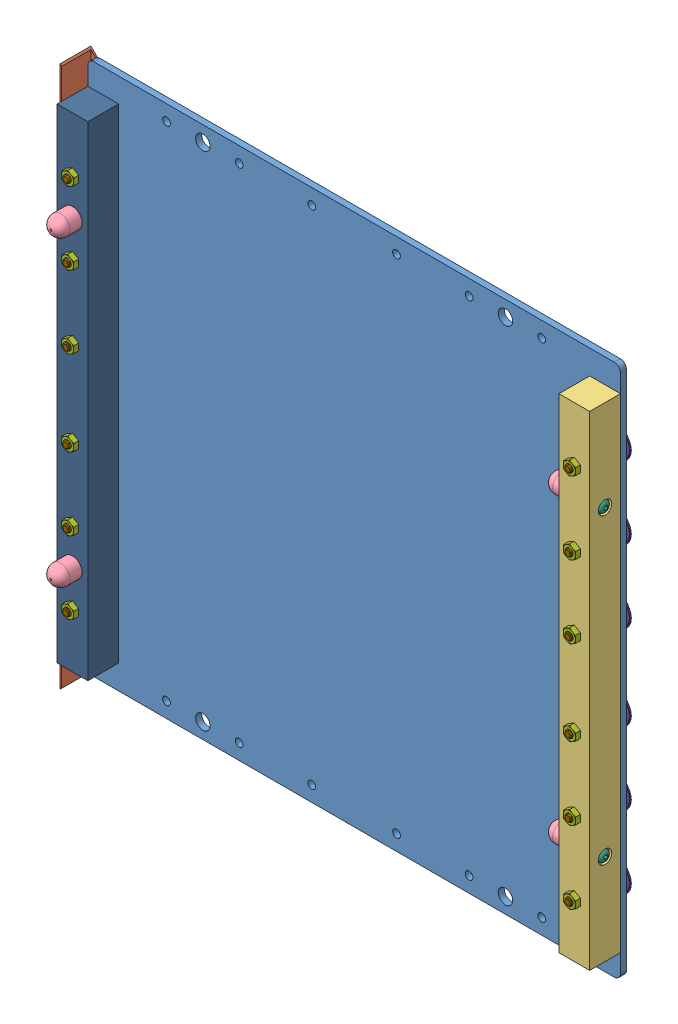
SolidWorks assembly Bed_MainAssembly, configuration Default. Lengths in mm.
Overall size (447.67 447.54 58.62).
61 component instances, 12 part files, 129 mates.
Components (placement in the parent):
- Bed_5mm-1: Bed_5mm [Default] at origin size (440 440 5)
- BedFrame-1: BedFrame [Default] at (-223.77 0 -1.27) x (0 0 1) z (0 1 0) size (25.4 25.4 447.54) (hidden)
- BedFrame-2: BedFrame [Default] at (0 -223.77 -1.27) x (0 0 1) z (-1 0 0) size (25.4 25.4 447.54) (hidden)
- BedFrame-3: BedFrame [Default] at (223.77 0 -1.27) x (0 0 1) z (0 -1 0) size (25.4 25.4 447.54) (hidden)
- BedFrame-4: BedFrame [Default] at (0 223.77 -1.27) x (0 0 1) z (1 0 0) size (25.4 25.4 447.54) (hidden)
- BedFrame_DelrinBar-1: BedFrame_DelrinBar [Default] at (207.3 0 17.7) x (0 0 -1) z (0 -1 0) size (25.4 25.4 400)
- CJPQTBB12_16-1: CJPQTBB12_16 [Default] at (194.6 125 17.7) x (-1 0 0) z (0 -0.914699 0.404136) size (32.96 16 16)
- CJPQTBB12_16-2: CJPQTBB12_16 [Default] at (194.6 -125 17.7) x (-1 0 0) z (0 -0.761161 -0.648564) size (32.96 16 16)
- M5_ss_93475A240-1: M5_ss_93475A240 [93475A240] at (217 -125 17.7) x (0 0 1) z (-1 0 0) size (10 10 0.9)
- M5_ss_93475A240-2: M5_ss_93475A240 [93475A240] at (217 125 17.7) x (0 0 1) z (-1 0 0) size (10 10 0.9)
- button_M5x20_92095A214-1: button_M5x20_92095A214 [92095A214] at (197.9 125 17.7) x (0 0 1) z (-1 0 0) size (9.5 9.5 23.15)
- button_M5x20_92095A214-2: button_M5x20_92095A214 [92095A214] at (197.9 -125 17.7) x (0 0.963052 -0.269316) z (-1 0 0) size (9.5 9.5 23.15)
- Captive_M6_97648A440-1: Captive_M6_97648A440 [97648A440] at (207.3 155 34.5) size (10 11.55 5.74)
- Captive_M6_97648A440-2: Captive_M6_97648A440 [97648A440] at (207.3 95 34.5) size (10 11.55 5.74)
- Captive_M6_97648A440-3: Captive_M6_97648A440 [97648A440] at (207.3 35 34.5) size (10 11.55 5.74)
- Captive_M6_97648A440-4: Captive_M6_97648A440 [97648A440] at (207.3 -35 34.5) size (10 11.55 5.74)
- Captive_M6_97648A440-5: Captive_M6_97648A440 [97648A440] at (207.3 -95 34.5) size (10 11.55 5.74)
- Captive_M6_97648A440-6: Captive_M6_97648A440 [97648A440] at (207.3 -155 34.5) size (10 11.55 5.74)
- 1-4_silicone_ss_91195A107-1: 1-4_silicone_ss_91195A107 [91195A107] at (207.3 -155 -3.9688) x (-0.923728 -0.383049 0) z (0 0 -1) size (25.4 25.4 3.97)
- 1-4_silicone_ss_91195A107-2: 1-4_silicone_ss_91195A107 [91195A107] at (207.3 -95 -3.9688) x (-0.923728 -0.383049 0) z (0 0 -1) size (25.4 25.4 3.97)
- 1-4_silicone_ss_91195A107-3: 1-4_silicone_ss_91195A107 [91195A107] at (207.3 -35 -3.9688) x (-0.923728 -0.383049 0) z (0 0 -1) size (25.4 25.4 3.97)
- 1-4_silicone_ss_91195A107-4: 1-4_silicone_ss_91195A107 [91195A107] at (207.3 35 -3.9688) x (-0.923728 -0.383049 0) z (0 0 -1) size (25.4 25.4 3.97)
- 1-4_silicone_ss_91195A107-5: 1-4_silicone_ss_91195A107 [91195A107] at (207.3 95 -3.9688) x (-0.923728 -0.383049 0) z (0 0 -1) size (25.4 25.4 3.97)
- 1-4_silicone_ss_91195A107-6: 1-4_silicone_ss_91195A107 [91195A107] at (207.3 155 -3.9688) x (-0.923728 -0.383049 0) z (0 0 -1) size (25.4 25.4 3.97)
- M6x40_91292A142-2: M6x40_91292A142 [91292A142] at (207.3 155 36.0312) size (10 10 46.57)
- M6x40_91292A142-3: M6x40_91292A142 [91292A142] at (207.3 95 36.0312) size (10 10 46.57)
- M6x40_91292A142-4: M6x40_91292A142 [91292A142] at (207.3 35 36.0312) size (10 10 46.57)
- M6x40_91292A142-5: M6x40_91292A142 [91292A142] at (207.3 -35 36.0312) size (10 10 46.57)
- M6x40_91292A142-6: M6x40_91292A142 [91292A142] at (207.3 -95 36.0312) size (10 10 46.57)
- M6x40_91292A142-7: M6x40_91292A142 [91292A142] at (207.3 -155 36.0312) size (10 10 46.57)
- BedFrame_LowerBar-1: BedFrame_LowerBar [Default] at (-207.3 0 17.7) x (0 0 -1) z (0 -1 0) size (25.4 25.4 400)
- CJPQTBB12_16-5: CJPQTBB12_16 [Default] at (-207.3 125 30.4) x (0 0 1) z (-1 0 0) size (32.96 16 16)
- CJPQTBB12_16-6: CJPQTBB12_16 [Default] at (-207.3 -125 30.4) x (0 0 1) z (-1 0 0) size (32.96 16 16)
- M5_ss_93475A240-3: M5_ss_93475A240 [93475A240] at (-207.3 125 8) size (10 10 0.9)
- M5_ss_93475A240-4: M5_ss_93475A240 [93475A240] at (-207.3 -125 8) size (10 10 0.9)
- button_M5x20_92095A214-3: button_M5x20_92095A214 [92095A214] at (-207.3 125 27.1) size (9.5 9.5 23.15)
- button_M5x20_92095A214-4: button_M5x20_92095A214 [92095A214] at (-207.3 -125 27.1) size (9.5 9.5 23.15)
- Captive_M6_97648A440-7: Captive_M6_97648A440 [97648A440] at (-207.3 -155 34.5) size (10 11.55 5.74)
- Captive_M6_97648A440-8: Captive_M6_97648A440 [97648A440] at (-207.3 -35 34.5) size (10 11.55 5.74)
- Captive_M6_97648A440-9: Captive_M6_97648A440 [97648A440] at (-207.3 35 34.5) size (10 11.55 5.74)
- Captive_M6_97648A440-10: Captive_M6_97648A440 [97648A440] at (-207.3 95 34.5) size (10 11.55 5.74)
- Captive_M6_97648A440-11: Captive_M6_97648A440 [97648A440] at (-207.3 -95 34.5) size (10 11.55 5.74)
- Captive_M6_97648A440-12: Captive_M6_97648A440 [97648A440] at (-207.3 155 34.5) size (10 11.55 5.74)
- 1-4_silicone_99604A115-1: 1-4_silicone_99604A115 [99604A115] at (-207.3 -155 0) size (15.88 15.88 2.36)
- 1-4_silicone_99604A115-2: 1-4_silicone_99604A115 [99604A115] at (-207.3 -95 0) size (15.88 15.88 2.36)
- 1-4_silicone_99604A115-3: 1-4_silicone_99604A115 [99604A115] at (-207.3 -35 0) size (15.88 15.88 2.36)
- 1-4_silicone_99604A115-4: 1-4_silicone_99604A115 [99604A115] at (-207.3 35 0) size (15.88 15.88 2.36)
- 1-4_silicone_99604A115-5: 1-4_silicone_99604A115 [99604A115] at (-207.3 95 0) size (15.88 15.88 2.36)
- 1-4_silicone_99604A115-6: 1-4_silicone_99604A115 [99604A115] at (-207.3 155 0) size (15.88 15.88 2.36)
- M6_ss_93475A250-1: M6_ss_93475A250 [93475A250] at (-207.3 -155 -2.3622) size (12 12 1.4)
- M6_ss_93475A250-2: M6_ss_93475A250 [93475A250] at (-207.3 -95 -2.3622) size (12 12 1.4)
- M6_ss_93475A250-3: M6_ss_93475A250 [93475A250] at (-207.3 -35 -2.3622) size (12 12 1.4)
- M6_ss_93475A250-4: M6_ss_93475A250 [93475A250] at (-207.3 35 -2.3622) size (12 12 1.4)
- M6_ss_93475A250-5: M6_ss_93475A250 [93475A250] at (-207.3 95 -2.3622) size (12 12 1.4)
- M6_ss_93475A250-6: M6_ss_93475A250 [93475A250] at (-207.3 155 -2.3622) size (12 12 1.4)
- M6x40_91292A142-8: M6x40_91292A142 [91292A142] at (-207.3 -155 36.2378) size (10 10 46.57)
- M6x40_91292A142-9: M6x40_91292A142 [91292A142] at (-207.3 -95 36.2378) size (10 10 46.57)
- M6x40_91292A142-10: M6x40_91292A142 [91292A142] at (-207.3 -35 36.2378) size (10 10 46.57)
- M6x40_91292A142-11: M6x40_91292A142 [91292A142] at (-207.3 35 36.2378) size (10 10 46.57)
- M6x40_91292A142-12: M6x40_91292A142 [91292A142] at (-207.3 95 36.2378) size (10 10 46.57)
- M6x40_91292A142-13: M6x40_91292A142 [91292A142] at (-207.3 155 36.2378) size (10 10 46.57)
Mates (geometry in assembly coordinates):
- Coincident1: coincident aligned: plane of Bed_5mm-1 through (0 0 0) normal (0 0 1); plane of assembly through (0 0 0) normal (0 0 1)
- Coincident2: coincident aligned: plane of Bed_5mm-1 through (0 0 0) normal (0 1 0); plane of assembly through (0 0 0) normal (0 1 0)
- Coincident3: coincident aligned: plane of Bed_5mm-1 through (0 0 0) normal (1 0 0); plane of assembly through (0 0 0) normal (1 0 0)
- Coincident4: coincident anti-aligned: plane of Bed_5mm-1 through (-220 -220 0) normal (0 0 -1); plane of BedFrame-1 through (-222.5 -304.8 0) normal (0 0 1)
- Coincident5: coincident anti-aligned: plane of Bed_5mm-1 through (-220 -220 0) normal (0 0 -1); plane of BedFrame-2 through (304.8 -222.5 0) normal (0 0 1)
- Coincident6: coincident anti-aligned: plane of Bed_5mm-1 through (-220 -220 0) normal (0 0 -1); plane of BedFrame-3 through (222.5 304.8 0) normal (0 0 1)
- Coincident7: coincident anti-aligned: plane of Bed_5mm-1 through (-220 -220 0) normal (0 0 -1); plane of BedFrame-4 through (-304.8 222.5 0) normal (0 0 1)
- Coincident8: coincident anti-aligned: plane of BedFrame-1 through (-198.37 -198.37 24.13) normal (0.707107 -0.707107 0); plane of BedFrame-2 through (-223.77 -223.77 24.13) normal (-0.707107 0.707107 0)
- Coincident10: coincident aligned: line of BedFrame-1 through (-223.77 -223.77 24.13) axis (0 0 -1); line of BedFrame-2 through (-223.77 -223.77 24.13) axis (0 0 -1)
- Coincident11: coincident anti-aligned: plane of BedFrame-2 through (198.37 -198.37 24.13) normal (0.707107 0.707107 0); plane of BedFrame-3 through (223.77 -223.77 24.13) normal (-0.707107 -0.707107 0)
- Coincident12: coincident aligned: line of BedFrame-2 through (223.77 -223.77 24.13) axis (0 0 -1); line of BedFrame-3 through (223.77 -223.77 24.13) axis (0 0 -1)
- Coincident13: coincident anti-aligned: plane of BedFrame-3 through (198.37 198.37 24.13) normal (-0.707107 0.707107 0); plane of BedFrame-4 through (223.77 223.77 24.13) normal (0.707107 -0.707107 0)
- Coincident14: coincident aligned: line of BedFrame-3 through (223.77 223.77 24.13) axis (0 0 -1); line of BedFrame-4 through (223.77 223.77 24.13) axis (0 0 -1)
- Coincident15: coincident aligned: plane of BedFrame-1 through (-223.77 0 -1.27) normal (0 1 0); plane of assembly through (0 0 0) normal (0 1 0)
- Coincident16: coincident anti-aligned: plane of Bed_5mm-1 through (0 0 0) normal (1 0 0); plane of BedFrame-2 through (0 -223.77 -1.27) normal (-1 0 0)
- Coincident17: coincident anti-aligned: plane of BedFrame_DelrinBar-1 through (207.3 0 17.7) normal (0 -1 0); plane of assembly through (0 0 0) normal (0 1 0)
- Coincident18: coincident anti-aligned: plane of Bed_5mm-1 through (-220 -220 5) normal (0 0 1); plane of BedFrame_DelrinBar-1 through (194.6 200 5) normal (0 0 -1)
- Coincident19: coincident aligned: plane of Bed_5mm-1 through (220 220 5) normal (1 0 0); plane of BedFrame_DelrinBar-1 through (220 200 5) normal (1 0 0)
- Concentric2: concentric aligned: cylinder of BedFrame_DelrinBar-1 through (230.8107 -125 17.7) axis (1 0 0) radius 6; cylinder of CJPQTBB12_16-2 through (194.5 -125 17.7) axis (1 0 0) radius 6
- Concentric3: concentric aligned: cylinder of BedFrame_DelrinBar-1 through (230.8107 125 17.7) axis (1 0 0) radius 6; cylinder of CJPQTBB12_16-1 through (194.5 125 17.7) axis (1 0 0) radius 6
- Coincident20: coincident anti-aligned: plane of BedFrame_DelrinBar-1 through (217 127.75 17.7) normal (1 0 0); plane of M5_ss_93475A240-2 through (217 125 17.7) normal (-1 0 0)
- Coincident21: coincident anti-aligned: plane of BedFrame_DelrinBar-1 through (217 -127.75 17.7) normal (1 0 0); plane of M5_ss_93475A240-1 through (217 -125 17.7) normal (-1 0 0)
- Concentric4: concentric anti-aligned: cylinder of BedFrame_DelrinBar-1 through (230.8107 -125 17.7) axis (1 0 0) radius 5.5563; cylinder of M5_ss_93475A240-1 through (217.9 -125 17.7) axis (-1 0 0) radius 5
- Concentric5: concentric anti-aligned: cylinder of BedFrame_DelrinBar-1 through (230.8107 125 17.7) axis (1 0 0) radius 5.5563; cylinder of M5_ss_93475A240-2 through (217.9 125 17.7) axis (-1 0 0) radius 5
- Concentric6: concentric anti-aligned: cylinder of BedFrame_DelrinBar-1 through (230.8107 125 17.7) axis (1 0 0) radius 5.5563; cylinder of button_M5x20_92095A214-1 through (220.65 125 17.7) axis (-1 0 0) radius 4.75
- Coincident22: coincident anti-aligned: plane of M5_ss_93475A240-2 through (217.9 125 17.7) normal (1 0 0); plane of button_M5x20_92095A214-1 through (217.9 125 17.7) normal (-1 0 0)
- Concentric7: concentric anti-aligned: cylinder of BedFrame_DelrinBar-1 through (230.8107 -125 17.7) axis (1 0 0) radius 5.5563; cylinder of button_M5x20_92095A214-2 through (220.65 -125 17.7) axis (-1 0 0) radius 4.75
- Coincident23: coincident anti-aligned: plane of M5_ss_93475A240-1 through (217.9 -125 17.7) normal (1 0 0); plane of button_M5x20_92095A214-2 through (217.9 -125 17.7) normal (-1 0 0)
- Coincident24: coincident anti-aligned: plane of BedFrame_DelrinBar-1 through (194.6 200 5) normal (-1 0 0); plane of CJPQTBB12_16-2 through (194.6 -125 17.7) normal (1 0 0)
- Coincident25: coincident anti-aligned: plane of BedFrame_DelrinBar-1 through (194.6 200 5) normal (-1 0 0); plane of CJPQTBB12_16-1 through (194.6 125 17.7) normal (1 0 0)
- Coincident26: coincident aligned: plane of Captive_M6_97648A440-1 through (202.3 163.6603 30.4) normal (0 0 -1); plane of Captive_M6_97648A440-6 through (202.3 -146.3397 30.4) normal (0 0 -1)
- Coincident27: coincident aligned: plane of Captive_M6_97648A440-4 through (202.3 -26.3397 30.4) normal (0 0 -1); plane of Captive_M6_97648A440-6 through (202.3 -146.3397 30.4) normal (0 0 -1)
- Coincident28: coincident aligned: plane of Captive_M6_97648A440-5 through (202.3 -86.3397 30.4) normal (0 0 -1); plane of Captive_M6_97648A440-6 through (202.3 -146.3397 30.4) normal (0 0 -1)
- Coincident29: coincident aligned: plane of Captive_M6_97648A440-3 through (202.3 43.6603 30.4) normal (0 0 -1); plane of Captive_M6_97648A440-6 through (202.3 -146.3397 30.4) normal (0 0 -1)
- Coincident30: coincident aligned: plane of Captive_M6_97648A440-2 through (202.3 103.6603 30.4) normal (0 0 -1); plane of Captive_M6_97648A440-6 through (202.3 -146.3397 30.4) normal (0 0 -1)
- Coincident31: coincident anti-aligned: plane of BedFrame_DelrinBar-1 through (194.6 200 30.4) normal (0 0 1); plane of Captive_M6_97648A440-6 through (202.3 -146.3397 30.4) normal (0 0 -1)
- Concentric8: concentric anti-aligned: cylinder of BedFrame_DelrinBar-1 through (207.3 -155 27.4) axis (0 0 1) radius 4; circle of Captive_M6_97648A440-6
- Concentric9: concentric anti-aligned: cylinder of BedFrame_DelrinBar-1 through (207.3 -95 27.4) axis (0 0 1) radius 4; circle of Captive_M6_97648A440-5
- Concentric10: concentric anti-aligned: cylinder of BedFrame_DelrinBar-1 through (207.3 -35 27.4) axis (0 0 1) radius 4; circle of Captive_M6_97648A440-4
- Concentric11: concentric anti-aligned: cylinder of BedFrame_DelrinBar-1 through (207.3 35 27.4) axis (0 0 1) radius 4; circle of Captive_M6_97648A440-3
- Concentric12: concentric anti-aligned: cylinder of BedFrame_DelrinBar-1 through (207.3 95 27.4) axis (0 0 1) radius 4; circle of Captive_M6_97648A440-2
- Concentric13: concentric anti-aligned: cylinder of BedFrame_DelrinBar-1 through (207.3 155 27.4) axis (0 0 1) radius 4; circle of Captive_M6_97648A440-1
- Coincident32: coincident aligned: plane of 1-4_silicone_ss_91195A107-1 through (207.3 -155 0) normal (0 0 1); plane of 1-4_silicone_ss_91195A107-2 through (207.3 -95 0) normal (0 0 1)
- Coincident33: coincident aligned: plane of 1-4_silicone_ss_91195A107-1 through (207.3 -155 0) normal (0 0 1); plane of 1-4_silicone_ss_91195A107-3 through (207.3 -35 0) normal (0 0 1)
- Coincident34: coincident aligned: plane of 1-4_silicone_ss_91195A107-1 through (207.3 -155 0) normal (0 0 1); plane of 1-4_silicone_ss_91195A107-4 through (207.3 35 0) normal (0 0 1)
- Coincident35: coincident aligned: plane of 1-4_silicone_ss_91195A107-1 through (207.3 -155 0) normal (0 0 1); plane of 1-4_silicone_ss_91195A107-5 through (207.3 95 0) normal (0 0 1)
- Coincident36: coincident aligned: plane of 1-4_silicone_ss_91195A107-1 through (207.3 -155 0) normal (0 0 1); plane of 1-4_silicone_ss_91195A107-6 through (207.3 155 0) normal (0 0 1)
- Coincident37: coincident anti-aligned: plane of Bed_5mm-1 through (-220 -220 0) normal (0 0 -1); plane of 1-4_silicone_ss_91195A107-1 through (207.3 -155 0) normal (0 0 1)
- Concentric15: concentric aligned: cylinder of BedFrame_DelrinBar-1 through (207.3 -155 30.4) axis (0 0 -1) radius 3.2; cylinder of 1-4_silicone_ss_91195A107-1 through (207.3 -155 38.0937) axis (0 0 -1) radius 12.065
- Concentric16: concentric aligned: cylinder of BedFrame_DelrinBar-1 through (207.3 -95 30.4) axis (0 0 -1) radius 3.2; cylinder of 1-4_silicone_ss_91195A107-2 through (207.3 -95 38.0937) axis (0 0 -1) radius 12.065
- Concentric17: concentric aligned: cylinder of BedFrame_DelrinBar-1 through (207.3 -35 30.4) axis (0 0 -1) radius 3.2; cylinder of 1-4_silicone_ss_91195A107-3 through (207.3 -35 38.0937) axis (0 0 -1) radius 12.065
- Concentric18: concentric aligned: cylinder of BedFrame_DelrinBar-1 through (207.3 35 30.4) axis (0 0 -1) radius 3.2; cylinder of 1-4_silicone_ss_91195A107-4 through (207.3 35 38.0937) axis (0 0 -1) radius 12.065
- Concentric19: concentric aligned: cylinder of BedFrame_DelrinBar-1 through (207.3 95 30.4) axis (0 0 -1) radius 3.2; cylinder of 1-4_silicone_ss_91195A107-5 through (207.3 95 38.0937) axis (0 0 -1) radius 12.065
- Concentric20: concentric aligned: cylinder of BedFrame_DelrinBar-1 through (207.3 155 30.4) axis (0 0 -1) radius 3.2; cylinder of 1-4_silicone_ss_91195A107-6 through (207.3 155 38.0937) axis (0 0 -1) radius 12.065
- Coincident38: coincident aligned: plane of M6x40_91292A142-6 through (207.3 -95 -3.9688) normal (0 0 1); plane of M6x40_91292A142-7 through (207.3 -155 -3.9688) normal (0 0 1)
- Coincident39: coincident aligned: plane of M6x40_91292A142-5 through (207.3 -35 -3.9688) normal (0 0 1); plane of M6x40_91292A142-7 through (207.3 -155 -3.9688) normal (0 0 1)
- Coincident40: coincident aligned: plane of M6x40_91292A142-4 through (207.3 35 -3.9688) normal (0 0 1); plane of M6x40_91292A142-7 through (207.3 -155 -3.9688) normal (0 0 1)
- Coincident41: coincident aligned: plane of M6x40_91292A142-3 through (207.3 95 -3.9688) normal (0 0 1); plane of M6x40_91292A142-7 through (207.3 -155 -3.9688) normal (0 0 1)
- Coincident42: coincident aligned: plane of M6x40_91292A142-2 through (207.3 155 -3.9688) normal (0 0 1); plane of M6x40_91292A142-7 through (207.3 -155 -3.9688) normal (0 0 1)
- Coincident43: coincident anti-aligned: plane of 1-4_silicone_ss_91195A107-2 through (207.3 -95 -3.9688) normal (0 0 -1); plane of M6x40_91292A142-7 through (207.3 -155 -3.9688) normal (0 0 1)
- Concentric21: concentric anti-aligned: cylinder of 1-4_silicone_ss_91195A107-1 through (207.3 -155 38.0937) axis (0 0 -1) radius 12.065; cylinder of M6x40_91292A142-7 through (207.3 -155 -9.9688) axis (0 0 1) radius 5
- Concentric22: concentric anti-aligned: cylinder of 1-4_silicone_ss_91195A107-2 through (207.3 -95 38.0937) axis (0 0 -1) radius 12.065; cylinder of M6x40_91292A142-6 through (207.3 -95 -9.9688) axis (0 0 1) radius 5
- Concentric23: concentric anti-aligned: cylinder of 1-4_silicone_ss_91195A107-3 through (207.3 -35 38.0937) axis (0 0 -1) radius 12.065; cylinder of M6x40_91292A142-5 through (207.3 -35 -9.9688) axis (0 0 1) radius 5
- Concentric24: concentric anti-aligned: cylinder of 1-4_silicone_ss_91195A107-4 through (207.3 35 38.0937) axis (0 0 -1) radius 12.065; cylinder of M6x40_91292A142-4 through (207.3 35 -9.9688) axis (0 0 1) radius 5
- Concentric25: concentric anti-aligned: cylinder of 1-4_silicone_ss_91195A107-5 through (207.3 95 38.0937) axis (0 0 -1) radius 12.065; cylinder of M6x40_91292A142-3 through (207.3 95 -9.9688) axis (0 0 1) radius 5
- Concentric26: concentric anti-aligned: cylinder of 1-4_silicone_ss_91195A107-6 through (207.3 155 38.0937) axis (0 0 -1) radius 12.065; cylinder of M6x40_91292A142-2 through (207.3 155 -9.9688) axis (0 0 1) radius 5
- Coincident53: coincident anti-aligned: plane of Bed_5mm-1 through (-220 -220 5) normal (0 0 1); plane of BedFrame_LowerBar-1 through (-220 200 5) normal (0 0 -1)
- Coincident54: coincident anti-aligned: plane of BedFrame_LowerBar-1 through (-207.3 0 17.7) normal (0 -1 0); plane of assembly through (0 0 0) normal (0 1 0)
- Coincident55: coincident aligned: plane of Bed_5mm-1 through (-220 220 5) normal (-1 0 0); plane of BedFrame_LowerBar-1 through (-220 200 5) normal (-1 0 0)
- Coincident56: coincident aligned: plane of button_M5x20_92095A214-3 through (-207.3 125 7.1) normal (0 0 1); plane of button_M5x20_92095A214-4 through (-207.3 -125 7.1) normal (0 0 1)
- Coincident57: coincident anti-aligned: plane of M5_ss_93475A240-4 through (-207.3 -125 7.1) normal (0 0 -1); plane of button_M5x20_92095A214-4 through (-207.3 -125 7.1) normal (0 0 1)
- Coincident58: coincident anti-aligned: plane of M5_ss_93475A240-3 through (-207.3 125 7.1) normal (0 0 -1); plane of button_M5x20_92095A214-3 through (-207.3 125 7.1) normal (0 0 1)
- Concentric28: concentric aligned: cylinder of M5_ss_93475A240-3 through (-207.3 125 7.1) axis (0 0 1) radius 5; cylinder of button_M5x20_92095A214-3 through (-207.3 125 4.35) axis (0 0 1) radius 4.75
- Concentric29: concentric aligned: cylinder of M5_ss_93475A240-4 through (-207.3 -125 7.1) axis (0 0 1) radius 5; cylinder of button_M5x20_92095A214-4 through (-207.3 -125 4.35) axis (0 0 1) radius 4.75
- Coincident59: coincident anti-aligned: plane of BedFrame_LowerBar-1 through (-207.3 119.4437 8) normal (0 0 -1); plane of M5_ss_93475A240-3 through (-207.3 125 8) normal (0 0 1)
- Concentric30: concentric anti-aligned: cylinder of BedFrame_LowerBar-1 through (-207.3 125 5) axis (0 0 -1) radius 5.5563; cylinder of M5_ss_93475A240-3 through (-207.3 125 7.1) axis (0 0 1) radius 5
- Concentric31: concentric anti-aligned: cylinder of BedFrame_LowerBar-1 through (-207.3 -125 5) axis (0 0 -1) radius 5.5563; cylinder of M5_ss_93475A240-4 through (-207.3 -125 7.1) axis (0 0 1) radius 5
- Coincident60: coincident aligned: plane of CJPQTBB12_16-5 through (-207.3 125 30.4) normal (0 0 -1); plane of CJPQTBB12_16-6 through (-207.3 -125 30.4) normal (0 0 -1)
- Concentric32: concentric aligned: cylinder of BedFrame_LowerBar-1 through (-207.3 -125 5) axis (0 0 -1) radius 6; cylinder of CJPQTBB12_16-6 through (-207.3 -125 30.5) axis (0 0 -1) radius 6
- Coincident61: coincident anti-aligned: plane of BedFrame_LowerBar-1 through (-220 200 30.4) normal (0 0 1); plane of CJPQTBB12_16-6 through (-207.3 -125 30.4) normal (0 0 -1)
- Concentric33: concentric aligned: cylinder of BedFrame_LowerBar-1 through (-207.3 125 5) axis (0 0 -1) radius 6; cylinder of CJPQTBB12_16-5 through (-207.3 125 30.5) axis (0 0 -1) radius 6
- Coincident62: coincident aligned: plane of Captive_M6_97648A440-7 through (-212.3 -146.3397 30.4) normal (0 0 -1); plane of Captive_M6_97648A440-12 through (-212.3 163.6603 30.4) normal (0 0 -1)
- Coincident63: coincident aligned: plane of Captive_M6_97648A440-7 through (-212.3 -146.3397 30.4) normal (0 0 -1); plane of Captive_M6_97648A440-9 through (-212.3 43.6603 30.4) normal (0 0 -1)
- Coincident64: coincident aligned: plane of Captive_M6_97648A440-7 through (-212.3 -146.3397 30.4) normal (0 0 -1); plane of Captive_M6_97648A440-11 through (-212.3 -86.3397 30.4) normal (0 0 -1)
- Coincident66: coincident aligned: plane of Captive_M6_97648A440-7 through (-212.3 -146.3397 30.4) normal (0 0 -1); plane of Captive_M6_97648A440-10 through (-212.3 103.6603 30.4) normal (0 0 -1)
- Coincident67: coincident aligned: plane of Captive_M6_97648A440-7 through (-212.3 -146.3397 30.4) normal (0 0 -1); plane of Captive_M6_97648A440-8 through (-212.3 -26.3397 30.4) normal (0 0 -1)
- Coincident68: coincident anti-aligned: plane of BedFrame_LowerBar-1 through (-220 200 30.4) normal (0 0 1); plane of Captive_M6_97648A440-7 through (-212.3 -146.3397 30.4) normal (0 0 -1)
- Concentric34: concentric anti-aligned: cylinder of BedFrame_LowerBar-1 through (-207.3 -155 27.4) axis (0 0 1) radius 4; circle of Captive_M6_97648A440-7
- Concentric35: concentric anti-aligned: cylinder of BedFrame_LowerBar-1 through (-207.3 -95 27.4) axis (0 0 1) radius 4; circle of Captive_M6_97648A440-11
- Concentric36: concentric anti-aligned: cylinder of BedFrame_LowerBar-1 through (-207.3 -35 27.4) axis (0 0 1) radius 4; circle of Captive_M6_97648A440-8
- Concentric37: concentric anti-aligned: cylinder of BedFrame_LowerBar-1 through (-207.3 35 27.4) axis (0 0 1) radius 4; circle of Captive_M6_97648A440-9
- Concentric38: concentric anti-aligned: cylinder of BedFrame_LowerBar-1 through (-207.3 95 27.4) axis (0 0 1) radius 4; circle of Captive_M6_97648A440-10
- Concentric39: concentric anti-aligned: cylinder of BedFrame_LowerBar-1 through (-207.3 155 27.4) axis (0 0 1) radius 4; circle of Captive_M6_97648A440-12
- Coincident69: coincident aligned: plane of 1-4_silicone_99604A115-1 through (-207.3 -155 0) normal (0 0 1); plane of 1-4_silicone_99604A115-2 through (-207.3 -95 0) normal (0 0 1)
- Coincident70: coincident aligned: plane of 1-4_silicone_99604A115-1 through (-207.3 -155 0) normal (0 0 1); plane of 1-4_silicone_99604A115-3 through (-207.3 -35 0) normal (0 0 1)
- Coincident71: coincident aligned: plane of 1-4_silicone_99604A115-1 through (-207.3 -155 0) normal (0 0 1); plane of 1-4_silicone_99604A115-4 through (-207.3 35 0) normal (0 0 1)
- Coincident72: coincident aligned: plane of 1-4_silicone_99604A115-1 through (-207.3 -155 0) normal (0 0 1); plane of 1-4_silicone_99604A115-5 through (-207.3 95 0) normal (0 0 1)
- Coincident73: coincident aligned: plane of 1-4_silicone_99604A115-1 through (-207.3 -155 0) normal (0 0 1); plane of 1-4_silicone_99604A115-6 through (-207.3 155 0) normal (0 0 1)
- Coincident74: coincident anti-aligned: plane of Bed_5mm-1 through (-220 -220 0) normal (0 0 -1); plane of 1-4_silicone_99604A115-1 through (-207.3 -155 0) normal (0 0 1)
- Concentric40: concentric anti-aligned: cylinder of BedFrame_LowerBar-1 through (-207.3 -155 30.4) axis (0 0 -1) radius 3.2; cylinder of 1-4_silicone_99604A115-1 through (-207.3 -155 -2.3622) axis (0 0 1) radius 7.9375
- Concentric41: concentric anti-aligned: cylinder of BedFrame_LowerBar-1 through (-207.3 -95 30.4) axis (0 0 -1) radius 3.2; cylinder of 1-4_silicone_99604A115-2 through (-207.3 -95 -2.3622) axis (0 0 1) radius 7.9375
- Concentric42: concentric anti-aligned: cylinder of BedFrame_LowerBar-1 through (-207.3 -35 30.4) axis (0 0 -1) radius 3.2; cylinder of 1-4_silicone_99604A115-3 through (-207.3 -35 -2.3622) axis (0 0 1) radius 7.9375
- Concentric43: concentric anti-aligned: cylinder of BedFrame_LowerBar-1 through (-207.3 35 30.4) axis (0 0 -1) radius 3.2; cylinder of 1-4_silicone_99604A115-4 through (-207.3 35 -2.3622) axis (0 0 1) radius 7.9375
- Concentric44: concentric anti-aligned: cylinder of BedFrame_LowerBar-1 through (-207.3 95 30.4) axis (0 0 -1) radius 3.2; cylinder of 1-4_silicone_99604A115-5 through (-207.3 95 -2.3622) axis (0 0 1) radius 7.9375
- Concentric45: concentric anti-aligned: cylinder of BedFrame_LowerBar-1 through (-207.3 155 30.4) axis (0 0 -1) radius 3.2; cylinder of 1-4_silicone_99604A115-6 through (-207.3 155 -2.3622) axis (0 0 1) radius 7.9375
- Coincident75: coincident anti-aligned: plane of M6_ss_93475A250-1 through (-207.3 -155 -3.7622) normal (0 0 -1); plane of M6x40_91292A142-8 through (-207.3 -155 -3.7622) normal (0 0 1)
- Coincident76: coincident anti-aligned: plane of M6_ss_93475A250-2 through (-207.3 -95 -3.7622) normal (0 0 -1); plane of M6x40_91292A142-9 through (-207.3 -95 -3.7622) normal (0 0 1)
- Concentric46: concentric aligned: cylinder of M6_ss_93475A250-1 through (-207.3 -155 -3.7622) axis (0 0 1) radius 6; cylinder of M6x40_91292A142-8 through (-207.3 -155 36.2378) axis (0 0 1) radius 3.127
- Concentric47: concentric aligned: cylinder of M6_ss_93475A250-2 through (-207.3 -95 -3.7622) axis (0 0 1) radius 6; cylinder of M6x40_91292A142-9 through (-207.3 -95 36.2378) axis (0 0 1) radius 3.127
- Concentric48: concentric aligned: cylinder of M6_ss_93475A250-3 through (-207.3 -35 -3.7622) axis (0 0 1) radius 6; cylinder of M6x40_91292A142-10 through (-207.3 -35 36.2378) axis (0 0 1) radius 3.127
- Coincident77: coincident anti-aligned: plane of M6_ss_93475A250-3 through (-207.3 -35 -3.7622) normal (0 0 -1); plane of M6x40_91292A142-10 through (-207.3 -35 -3.7622) normal (0 0 1)
- Concentric49: concentric aligned: cylinder of M6_ss_93475A250-4 through (-207.3 35 -3.7622) axis (0 0 1) radius 6; cylinder of M6x40_91292A142-11 through (-207.3 35 36.2378) axis (0 0 1) radius 3.127
- Coincident78: coincident anti-aligned: plane of M6_ss_93475A250-4 through (-207.3 35 -3.7622) normal (0 0 -1); plane of M6x40_91292A142-11 through (-207.3 35 -3.7622) normal (0 0 1)
- Concentric50: concentric aligned: cylinder of M6_ss_93475A250-5 through (-207.3 95 -3.7622) axis (0 0 1) radius 6; cylinder of M6x40_91292A142-12 through (-207.3 95 36.2378) axis (0 0 1) radius 3.127
- Coincident79: coincident anti-aligned: plane of M6_ss_93475A250-5 through (-207.3 95 -3.7622) normal (0 0 -1); plane of M6x40_91292A142-12 through (-207.3 95 -3.7622) normal (0 0 1)
- Concentric51: concentric aligned: cylinder of M6_ss_93475A250-6 through (-207.3 155 -3.7622) axis (0 0 1) radius 6; cylinder of M6x40_91292A142-13 through (-207.3 155 36.2378) axis (0 0 1) radius 3.127
- Coincident80: coincident anti-aligned: plane of M6_ss_93475A250-6 through (-207.3 155 -3.7622) normal (0 0 -1); plane of M6x40_91292A142-13 through (-207.3 155 -3.7622) normal (0 0 1)
- Coincident81: coincident aligned: plane of M6_ss_93475A250-5 through (-207.3 95 -2.3622) normal (0 0 1); plane of M6_ss_93475A250-6 through (-207.3 155 -2.3622) normal (0 0 1)
- Coincident82: coincident aligned: plane of M6_ss_93475A250-4 through (-207.3 35 -2.3622) normal (0 0 1); plane of M6_ss_93475A250-6 through (-207.3 155 -2.3622) normal (0 0 1)
- Coincident83: coincident aligned: plane of M6_ss_93475A250-3 through (-207.3 -35 -2.3622) normal (0 0 1); plane of M6_ss_93475A250-6 through (-207.3 155 -2.3622) normal (0 0 1)
- Coincident84: coincident aligned: plane of M6_ss_93475A250-2 through (-207.3 -95 -2.3622) normal (0 0 1); plane of M6_ss_93475A250-6 through (-207.3 155 -2.3622) normal (0 0 1)
- Coincident85: coincident aligned: plane of M6_ss_93475A250-1 through (-207.3 -155 -2.3622) normal (0 0 1); plane of M6_ss_93475A250-6 through (-207.3 155 -2.3622) normal (0 0 1)
- Concentric52: concentric aligned: cylinder of 1-4_silicone_99604A115-6 through (-207.3 155 -2.3622) axis (0 0 1) radius 2.921; cylinder of M6x40_91292A142-13 through (-207.3 155 36.2378) axis (0 0 1) radius 3.127
- Coincident86: coincident anti-aligned: plane of 1-4_silicone_99604A115-6 through (-207.3 155 -2.3622) normal (0 0 -1); plane of M6_ss_93475A250-6 through (-207.3 155 -2.3622) normal (0 0 1)
- Concentric53: concentric aligned: cylinder of 1-4_silicone_99604A115-1 through (-207.3 -155 -2.3622) axis (0 0 1) radius 7.9375; cylinder of M6x40_91292A142-8 through (-207.3 -155 -9.7622) axis (0 0 1) radius 5
- Concentric54: concentric aligned: cylinder of 1-4_silicone_99604A115-2 through (-207.3 -95 -2.3622) axis (0 0 1) radius 7.9375; cylinder of M6x40_91292A142-9 through (-207.3 -95 -9.7622) axis (0 0 1) radius 5
- Concentric55: concentric aligned: cylinder of 1-4_silicone_99604A115-3 through (-207.3 -35 -2.3622) axis (0 0 1) radius 7.9375; cylinder of M6x40_91292A142-10 through (-207.3 -35 -9.7622) axis (0 0 1) radius 5
- Concentric56: concentric aligned: cylinder of 1-4_silicone_99604A115-4 through (-207.3 35 -2.3622) axis (0 0 1) radius 7.9375; cylinder of M6x40_91292A142-11 through (-207.3 35 -9.7622) axis (0 0 1) radius 5
- Concentric57: concentric aligned: cylinder of 1-4_silicone_99604A115-5 through (-207.3 95 -2.3622) axis (0 0 1) radius 7.9375; cylinder of M6x40_91292A142-12 through (-207.3 95 -9.7622) axis (0 0 1) radius 5; sketch_entity of CJPQTBB12_16-6
